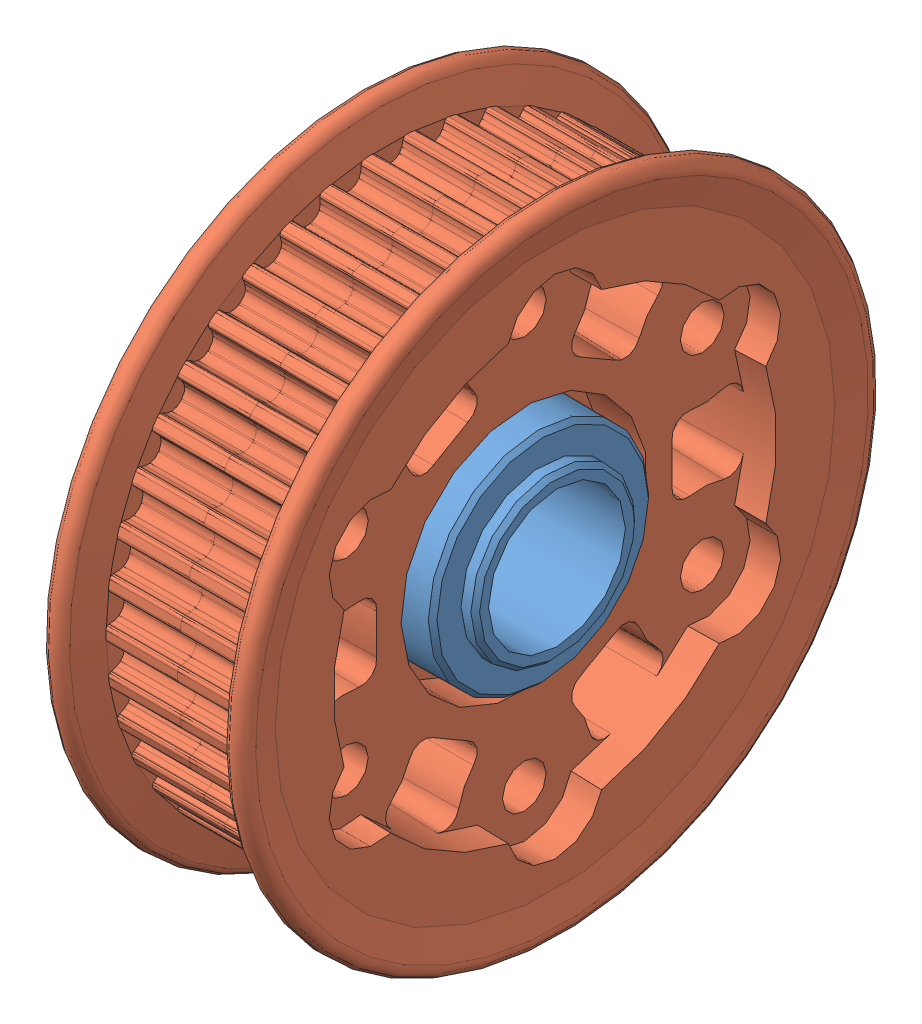
SolidWorks assembly BB_Pivot_Hub_Assem, configuration Default. Lengths in mm.
Overall size (28.06 101.39 101.39).
3 component instances, 2 part files, 6 mates.
Components (placement in the parent):
- _SWERVE_PIVOT_HUB_MOUNT-1: _SWERVE_PIVOT_HUB_MOUNT [Default] at (-35.8091 30.4937 44.9492) size (27.43 59.69 59.69)
- am-2234_42toothHTDpulleyHalfRev2-1: am-2234_42toothHTDpulleyHalfRev2 [Default] at (19.0549 30.4937 44.9492) x (1 0 0) z (0 -0.000084 -1) size (13 74.23 74.23)
- am-2234_42toothHTDpulleyHalfRev2-2: am-2234_42toothHTDpulleyHalfRev2 [Default] at (35.7173 30.4937 44.9492) x (-1 0 0) z (0 0.866067 0.499927) size (13 74.23 74.23)
Mates (geometry in assembly coordinates):
- Coincident1: coincident: plane of _SWERVE_PIVOT_HUB_MOUNT-1 through (20.0709 60.3387 44.9492) normal (1 0 0); plane of am-2234_42toothHTDpulleyHalfRev2-1 through (20.0709 30.4937 44.9492) normal (-1 0 0)
- Coincident2: coincident: plane of am-2234_42toothHTDpulleyHalfRev2-1 through (27.3861 -1.7043 44.8281) normal (1 0 0); plane of am-2234_42toothHTDpulleyHalfRev2-2 through (27.3861 14.5042 72.8967) normal (-1 0 0)
- Concentric2: concentric aligned: circle of _SWERVE_PIVOT_HUB_MOUNT-1; circle of am-2234_42toothHTDpulleyHalfRev2-2
- Coincident3: coincident: line of am-2234_42toothHTDpulleyHalfRev2-1 through (19.0549 56.4623 24.8152) axis (1 0 0); line of am-2234_42toothHTDpulleyHalfRev2-2 through (35.7173 56.4623 24.8152) axis (-1 0 0)
- Concentric3: concentric anti-aligned: circle of _SWERVE_PIVOT_HUB_MOUNT-1; circle of am-2234_42toothHTDpulleyHalfRev2-2
- Concentric4: concentric aligned: circle of am-2234_42toothHTDpulleyHalfRev2-1; circle of am-2234_42toothHTDpulleyHalfRev2-2
